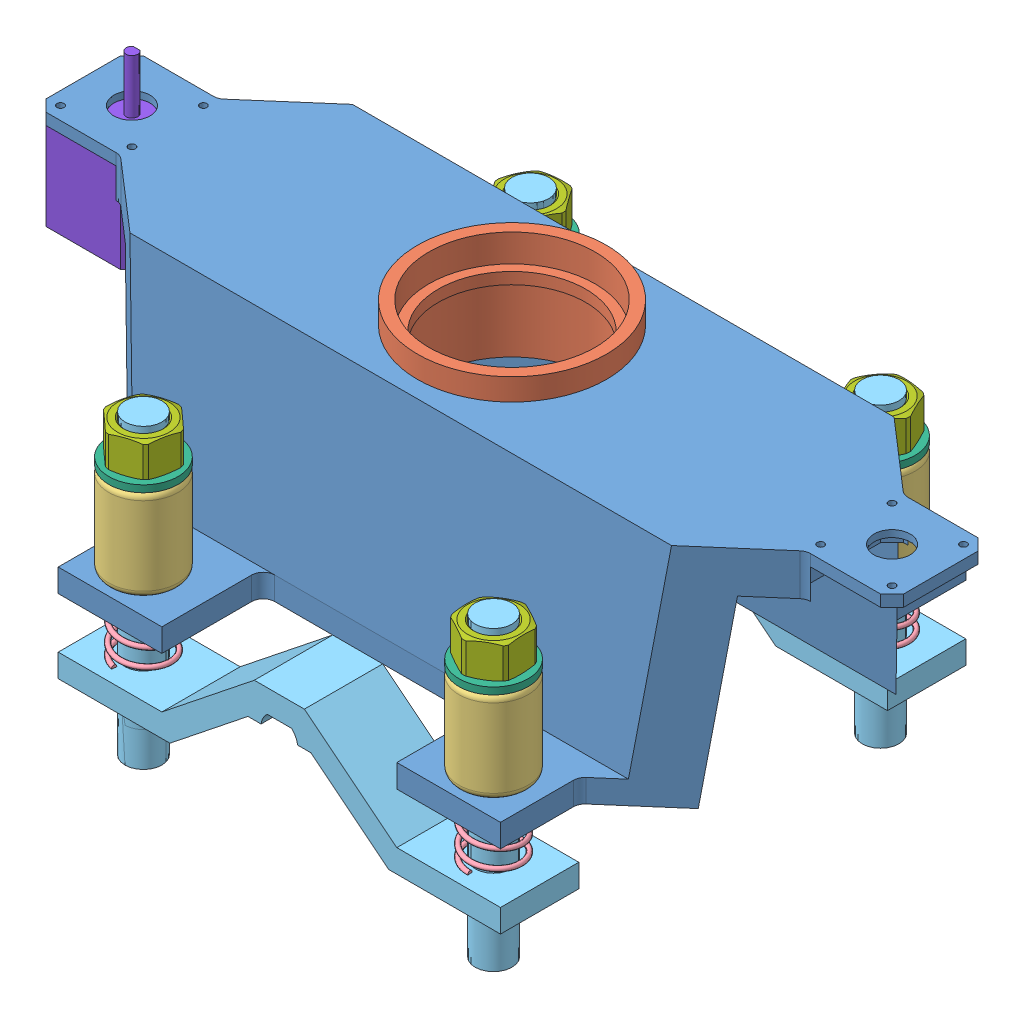
SolidWorks assembly ТП.SH21(K2).02.00 - Кронштейн ступицы поворотной, configuration 00. Lengths in mm.
Overall size (372.3 178 210.07).
21 component instances, 8 part files, 43 mates.
Components (placement in the parent):
- ТП.SH21(K2).02.01 - Каретка-1: ТП.SH21(K2).02.01 - Каретка [--] at origin size (372.3 98.5 202)
- ТП.SH21(K2).02.02 - Обойма 2007910А (2шт)-1: ТП.SH21(K2).02.02 - Обойма 2007910А (2шт) [--] at (0 -2.5 0) x (0 -1 0) z (-0.634197 0 -0.773171) size (47 82 82)
- Линейный подшипник (16х30х40)-1: Линейный подшипник (16х30х40) [--] at (-76 -63.5 84) x (-0.966713 0 0.255864) z (0 -1 0) size (30 30 40)
- Линейный подшипник (16х30х40)-2: Линейный подшипник (16х30х40) [--] at (76 -63.5 84) x (-0.901172 0 0.433461) z (0 -1 0) size (30 30 40)
- Линейный подшипник (16х30х40)-3: Линейный подшипник (16х30х40) [--] at (76 -63.5 -84) x (-0.786541 0 0.617538) z (0 -1 0) size (30 30 40)
- Линейный подшипник (16х30х40)-4: Линейный подшипник (16х30х40) [--] at (-76 -63.5 -84) x (-0.619852 0 0.784719) z (0 -1 0) size (30 30 40)
- ТП.SH21(K1).01.03 - Пружина 22х22х2-1: ТП.SH21(K1).01.03 - Пружина 22х22х2 [--] at (76 -93.75 -84) x (-0.837169 0 -0.546944) z (-0.546944 0 0.837169) size (24 22 24.59)
- ТП.SH21(K1).01.03 - Пружина 22х22х2-2: ТП.SH21(K1).01.03 - Пружина 22х22х2 [--] at (-76 -93.75 -84) x (-0.925243 0 -0.379375) z (-0.379375 0 0.925243) size (24 22 24.59)
- ТП.SH21(K1).01.03 - Пружина 22х22х2-3: ТП.SH21(K1).01.03 - Пружина 22х22х2 [--] at (-76 -93.75 84) x (-0.985271 0 -0.170998) z (-0.170998 0 0.985271) size (24 22 24.59)
- ТП.SH21(K1).01.03 - Пружина 22х22х2-4: ТП.SH21(K1).01.03 - Пружина 22х22х2 [--] at (76 -93.75 84) x (-0.997902 0 0.064746) z (0.064746 0 0.997902) size (24 22 24.59)
- ТП.SH21(K2).02.03 - Верхний кронштейн К2-1: ТП.SH21(K2).02.03 - Верхний кронштейн К2 [--] at (0 -99.5 -67) size (192 129 34)
- ТП.SH21(K2).02.03 - Верхний кронштейн К2-2: ТП.SH21(K2).02.03 - Верхний кронштейн К2 [--] at (0 -99.5 101) size (192 129 34)
- Шайбы (ГОСТ 11371-78)-1: Шайбы (ГОСТ 11371-78) [Шайба 16 ГОСТ 11371-78] at (76 -42 -84) x (0 -1 0) z (0 0 1) size (3 30 30)
- Гайка (ГОСТ ISO 4032-2014)-1: Гайка (ГОСТ ISO 4032-2014) [Гайка М16 (ГОСТ ISO 4032)] at (76 -33.1 -84) x (0.816213 0 0.577751) z (0 1 0) size (24 26.75 14.8)
- Гайка (ГОСТ ISO 4032-2014)-2: Гайка (ГОСТ ISO 4032-2014) [Гайка М16 (ГОСТ ISO 4032)] at (-76 -33.1 -84) x (0.910468 0 0.413579) z (0 1 0) size (24 26.75 14.8)
- Шайбы (ГОСТ 11371-78)-2: Шайбы (ГОСТ 11371-78) [Шайба 16 ГОСТ 11371-78] at (-76 -42 -84) x (0 -1 0) z (0.188455 0 0.982082) size (3 30 30)
- Гайка (ГОСТ ISO 4032-2014)-4: Гайка (ГОСТ ISO 4032-2014) [Гайка М16 (ГОСТ ISO 4032)] at (-76 -33.1 84) x (0.978217 0 0.207583) z (0 1 0) size (24 26.75 14.8)
- Шайбы (ГОСТ 11371-78)-4: Шайбы (ГОСТ 11371-78) [Шайба 16 ГОСТ 11371-78] at (-76 -42 84) x (0 -1 0) z (0.395734 0 0.918365) size (3 30 30)
- Гайка (ГОСТ ISO 4032-2014)-6: Гайка (ГОСТ ISO 4032-2014) [Гайка М16 (ГОСТ ISO 4032)] at (76 -33.1 84) x (0.999621 0 -0.027527) z (0 1 0) size (24 26.75 14.8)
- Шайбы (ГОСТ 11371-78)-6: Шайбы (ГОСТ 11371-78) [Шайба 16 ГОСТ 11371-78] at (76 -42 84) x (0 -1 0) z (0.6 0 0.8) size (3 30 30)
- 17HS4401 (Nema17)-1: 17HS4401 (Nema17) [--] at (-165 0 0) x (1 0 0) z (0 1 0) size (42.3 42.3 63.5)
Mates (geometry in assembly coordinates):
- Совпадение1: coincident: plane of ТП.SH21(K2).02.01 - Каретка-1 through (36 -32.5 0) normal (0 1 0); plane of ТП.SH21(K2).02.02 - Обойма 2007910А (2шт)-1 through (-27.8342 -32.5 22.8311) normal (0 -1 0)
- Концентричный1: concentric: cylinder of ТП.SH21(K2).02.01 - Каретка-1 through (0 997.5 0) axis (0 1 0) radius 41; cylinder of ТП.SH21(K2).02.02 - Обойма 2007910А (2шт)-1 through (0 997.5 0) axis (0 1 0) radius 41
- Совпадение2: coincident: plane of ТП.SH21(K2).02.01 - Каретка-1 through (-186.15 -83.5 101) normal (0 1 0); plane of Линейный подшипник (16х30х40)-1 through (-76 -83.5 84) normal (0 -1 0)
- Концентричный2: concentric: cylinder of ТП.SH21(K2).02.01 - Каретка-1 through (-76 5 84) axis (0 -1 0) radius 8.2; cylinder of Линейный подшипник (16х30х40)-1 through (-76 -83.5 84) axis (0 1 0) radius 8
- Совпадение3: coincident: plane of ТП.SH21(K2).02.01 - Каретка-1 through (-186.15 -83.5 101) normal (0 1 0); plane of Линейный подшипник (16х30х40)-2 through (76 -83.5 84) normal (0 -1 0)
- Концентричный3: concentric: cylinder of ТП.SH21(K2).02.01 - Каретка-1 through (76 5 84) axis (0 -1 0) radius 8.2; cylinder of Линейный подшипник (16х30х40)-2 through (76 -83.5 84) axis (0 1 0) radius 8
- Совпадение4: coincident: plane of ТП.SH21(K2).02.01 - Каретка-1 through (-186.15 -83.5 101) normal (0 1 0); plane of Линейный подшипник (16х30х40)-3 through (76 -83.5 -84) normal (0 -1 0)
- Концентричный4: concentric: cylinder of ТП.SH21(K2).02.01 - Каретка-1 through (76 5 -84) axis (0 -1 0) radius 8.2; cylinder of Линейный подшипник (16х30х40)-3 through (76 -83.5 -84) axis (0 1 0) radius 8
- Совпадение5: coincident: plane of ТП.SH21(K2).02.01 - Каретка-1 through (-186.15 -83.5 101) normal (0 1 0); plane of Линейный подшипник (16х30х40)-4 through (-76 -83.5 -84) normal (0 -1 0)
- Концентричный5: concentric: cylinder of ТП.SH21(K2).02.01 - Каретка-1 through (-76 5 -84) axis (0 -1 0) radius 8.2; cylinder of Линейный подшипник (16х30х40)-4 through (-76 -83.5 -84) axis (0 1 0) radius 8
- Совпадение7: coincident: plane of ТП.SH21(K2).02.01 - Каретка-1 through (-93.7909 -93.5 -72.0003) normal (0 -1 0); plane of ТП.SH21(K1).01.03 - Пружина 22х22х2-1 through (97.4572 -93.5 -84.3151) normal (0 1 0)
- Концентричный6: concentric: cylinder of ТП.SH21(K2).02.01 - Каретка-1 through (76 5 -84) axis (0 -1 0) radius 8.2; circle of ТП.SH21(K1).01.03 - Пружина 22х22х2-1
- Совпадение8: coincident: plane of ТП.SH21(K2).02.01 - Каретка-1 through (-93.7909 -93.5 -72.0003) normal (0 -1 0); plane of ТП.SH21(K1).01.03 - Пружина 22х22х2-2 through (-54.9867 -93.5 -88.3532) normal (0 1 0)
- Концентричный7: concentric: cylinder of ТП.SH21(K2).02.01 - Каретка-1 through (-76 5 -84) axis (0 -1 0) radius 8.2; circle of ТП.SH21(K1).01.03 - Пружина 22х22х2-2
- Совпадение9: coincident: plane of ТП.SH21(K2).02.01 - Каретка-1 through (-93.7909 -93.5 -72.0003) normal (0 -1 0); plane of ТП.SH21(K1).01.03 - Пружина 22х22х2-3 through (-56.4192 -93.5 75.2193) normal (0 1 0)
- Концентричный8: concentric: cylinder of ТП.SH21(K2).02.01 - Каретка-1 through (-76 5 84) axis (0 -1 0) radius 8.2; circle of ТП.SH21(K1).01.03 - Пружина 22х22х2-3
- Совпадение10: coincident: plane of ТП.SH21(K2).02.01 - Каретка-1 through (-93.7909 -93.5 -72.0003) normal (0 -1 0); plane of ТП.SH21(K1).01.03 - Пружина 22х22х2-4 through (92.9767 -93.5 70.8736) normal (0 1 0)
- Концентричный9: concentric: cylinder of ТП.SH21(K2).02.01 - Каретка-1 through (76 5 84) axis (0 -1 0) radius 8.2; circle of ТП.SH21(K1).01.03 - Пружина 22х22х2-4
- Совпадение12: coincident: plane of ТП.SH21(K1).01.03 - Пружина 22х22х2-1 through (97.4572 -115.5 -84.3151) normal (0 -1 0); plane of ТП.SH21(K2).02.03 - Верхний кронштейн К2-1 through (51 -115.5 -205.7855) normal (0 1 0)
- Концентричный10: concentric: cylinder of Линейный подшипник (16х30х40)-3 through (76 -83.5 -84) axis (0 1 0) radius 8; cylinder of ТП.SH21(K2).02.03 - Верхний кронштейн К2-1 through (76 19.1274 -84) axis (0 -1 0) radius 8
- Концентричный11: concentric: cylinder of Линейный подшипник (16х30х40)-4 through (-76 -83.5 -84) axis (0 1 0) radius 8; cylinder of ТП.SH21(K2).02.03 - Верхний кронштейн К2-1 through (-76 19.1274 -84) axis (0 -1 0) radius 8
- Совпадение13: coincident: plane of ТП.SH21(K1).01.03 - Пружина 22х22х2-4 through (92.9767 -115.5 70.8736) normal (0 -1 0); plane of ТП.SH21(K2).02.03 - Верхний кронштейн К2-2 through (51 -115.5 -37.7855) normal (0 1 0)
- Концентричный12: concentric: cylinder of Линейный подшипник (16х30х40)-2 through (76 -83.5 84) axis (0 1 0) radius 8; cylinder of ТП.SH21(K2).02.03 - Верхний кронштейн К2-2 through (76 19.1274 84) axis (0 -1 0) radius 8
- Концентричный13: concentric: cylinder of Линейный подшипник (16х30х40)-1 through (-76 -83.5 84) axis (0 1 0) radius 8; cylinder of ТП.SH21(K2).02.03 - Верхний кронштейн К2-2 through (-76 19.1274 84) axis (0 -1 0) radius 8
- Совпадение14: coincident: plane of Линейный подшипник (16х30х40)-3 through (76 -43.5 -84) normal (0 1 0); plane of Шайбы (ГОСТ 11371-78)-1 through (84.75 -43.5 -84) normal (0 -1 0)
- Концентричный14: concentric: cylinder of ТП.SH21(K2).02.03 - Верхний кронштейн К2-1 through (76 19.1274 -84) axis (0 -1 0) radius 8; cylinder of Шайбы (ГОСТ 11371-78)-1 through (76 958 -84) axis (0 1 0) radius 8.75
- Совпадение15: coincident: plane of Шайбы (ГОСТ 11371-78)-1 through (84.75 -40.5 -84) normal (0 1 0); plane of Гайка (ГОСТ ISO 4032-2014)-1 through (82.4997 -40.5 -93.1824) normal (0 -1 0)
- Концентричный15: concentric: cylinder of ТП.SH21(K2).02.03 - Верхний кронштейн К2-1 through (76 19.1274 -84) axis (0 -1 0) radius 8; cylinder of Гайка (ГОСТ ISO 4032-2014)-1 through (76 119.6402 -84) axis (0 1 0) radius 6.2679
- Совпадение16: coincident: plane of Гайка (ГОСТ ISO 4032-2014)-2 through (-71.3472 -40.5 -94.2428) normal (0 -1 0); plane of Шайбы (ГОСТ 11371-78)-2 through (-67.4068 -40.5 -85.649) normal (0 1 0)
- Совпадение17: coincident: plane of Линейный подшипник (16х30х40)-4 through (-76 -43.5 -84) normal (0 1 0); plane of Шайбы (ГОСТ 11371-78)-2 through (-67.4068 -43.5 -85.649) normal (0 -1 0)
- Концентричный16: concentric: cylinder of ТП.SH21(K2).02.03 - Верхний кронштейн К2-1 through (-76 19.1274 -84) axis (0 -1 0) radius 8; cylinder of Шайбы (ГОСТ 11371-78)-2 through (-76 958 -84) axis (0 1 0) radius 8.75
- Концентричный17: concentric: cylinder of ТП.SH21(K2).02.03 - Верхний кронштейн К2-1 through (-76 19.1274 -84) axis (0 -1 0) radius 8; cylinder of Гайка (ГОСТ ISO 4032-2014)-2 through (-76 119.6402 -84) axis (0 1 0) radius 6.2679
- Совпадение19: coincident: plane of Гайка (ГОСТ ISO 4032-2014)-4 through (-73.6647 -40.5 72.9951) normal (0 -1 0); plane of Шайбы (ГОСТ 11371-78)-4 through (-67.9643 -40.5 80.5373) normal (0 1 0)
- Совпадение20: coincident: plane of Линейный подшипник (16х30х40)-1 through (-76 -43.5 84) normal (0 1 0); plane of Шайбы (ГОСТ 11371-78)-4 through (-67.9643 -43.5 80.5373) normal (0 -1 0)
- Концентричный18: concentric: cylinder of ТП.SH21(K2).02.03 - Верхний кронштейн К2-2 through (-76 19.1274 84) axis (0 -1 0) radius 8; cylinder of Шайбы (ГОСТ 11371-78)-4 through (-76 958 84) axis (0 1 0) radius 8.75
- Концентричный19: concentric: cylinder of ТП.SH21(K2).02.03 - Верхний кронштейн К2-2 through (-76 19.1274 84) axis (0 -1 0) radius 8; cylinder of Гайка (ГОСТ ISO 4032-2014)-4 through (-76 119.6402 84) axis (0 1 0) radius 6.2679
- Совпадение22: coincident: plane of Гайка (ГОСТ ISO 4032-2014)-6 through (75.6903 -40.5 72.7543) normal (0 -1 0); plane of Шайбы (ГОСТ 11371-78)-6 through (83 -40.5 78.75) normal (0 1 0)
- Совпадение23: coincident: plane of Линейный подшипник (16х30х40)-2 through (76 -43.5 84) normal (0 1 0); plane of Шайбы (ГОСТ 11371-78)-6 through (83 -43.5 78.75) normal (0 -1 0)
- Концентричный20: concentric: cylinder of ТП.SH21(K2).02.03 - Верхний кронштейн К2-2 through (76 19.1274 84) axis (0 -1 0) radius 8; cylinder of Шайбы (ГОСТ 11371-78)-6 through (76 958 84) axis (0 1 0) radius 8.75
- Концентричный21: concentric: cylinder of ТП.SH21(K2).02.03 - Верхний кронштейн К2-2 through (76 19.1274 84) axis (0 -1 0) radius 8; cylinder of Гайка (ГОСТ ISO 4032-2014)-6 through (76 119.6402 84) axis (0 1 0) radius 6.2679
- Совпадение25: coincident: plane of ТП.SH21(K2).02.01 - Каретка-1 through (-165 0 0) normal (0 -1 0); plane of 17HS4401 (Nema17)-1 through (-165 0 0) normal (0 1 0)
- Совпадение26: coincident: plane of ТП.SH21(K2).02.01 - Каретка-1 through (-143.85 -38 16.15) normal (-1 0 0); plane of 17HS4401 (Nema17)-1 through (-143.85 -38 16.15) normal (1 0 0)
- Совпадение27: coincident: plane of ТП.SH21(K2).02.01 - Каретка-1 through (-143.85 -38 -16.15) normal (-0.707107 0 0.707107); plane of 17HS4401 (Nema17)-1 through (-148.85 -38 -21.15) normal (0.707107 0 -0.707107)
